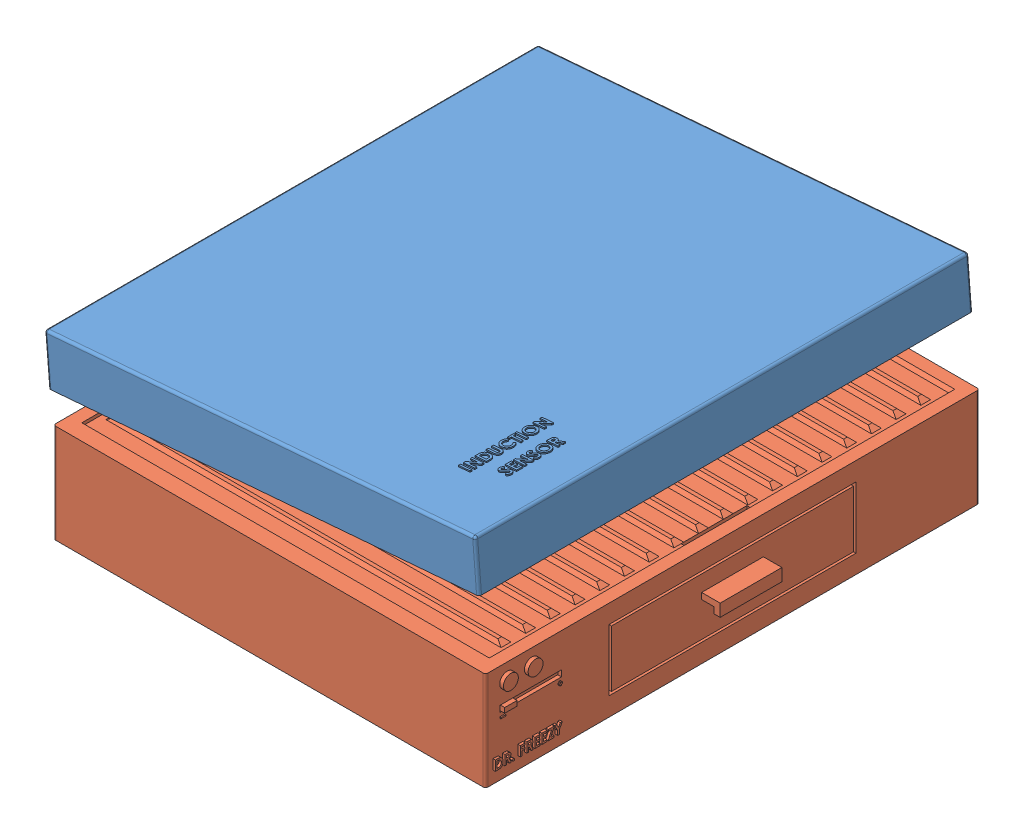
SolidWorks assembly Assembly tosti ijzer, configuration Default. Lengths in mm.
Overall size (497 172.92 400).
2 component instances, 2 part files, 2 mates.
Components (placement in the parent):
- tosti ijzer bovenkant-2: tosti ijzer bovenkant [Default] at (150.7269 384.9499 454.2465) x (0 0 -1) z (0.996651 0.081767 0) size (400 59 370)
- tosti ijzer onderkant-1: tosti ijzer onderkant [Default] at (155.4094 307.1998 454.2465) x (0 0 1) z (-1 0 0) size (400 99.33 497)
Mates (geometry in assembly coordinates):
- Concentric1: concentric aligned: cylinder of tosti ijzer onderkant-1 through (-32.5906 356.8665 520.2465) axis (0 0 -1) radius 5; cylinder of tosti ijzer bovenkant-2 through (-32.5906 356.8665 520.2465) axis (0 0 -1) radius 5
- Coincident1: coincident aligned: plane of tosti ijzer onderkant-1 through (-32.5906 356.8665 388.2465) normal (0 0 -1); plane of tosti ijzer bovenkant-2 through (-32.5906 356.8665 388.2465) normal (0 0 -1)
